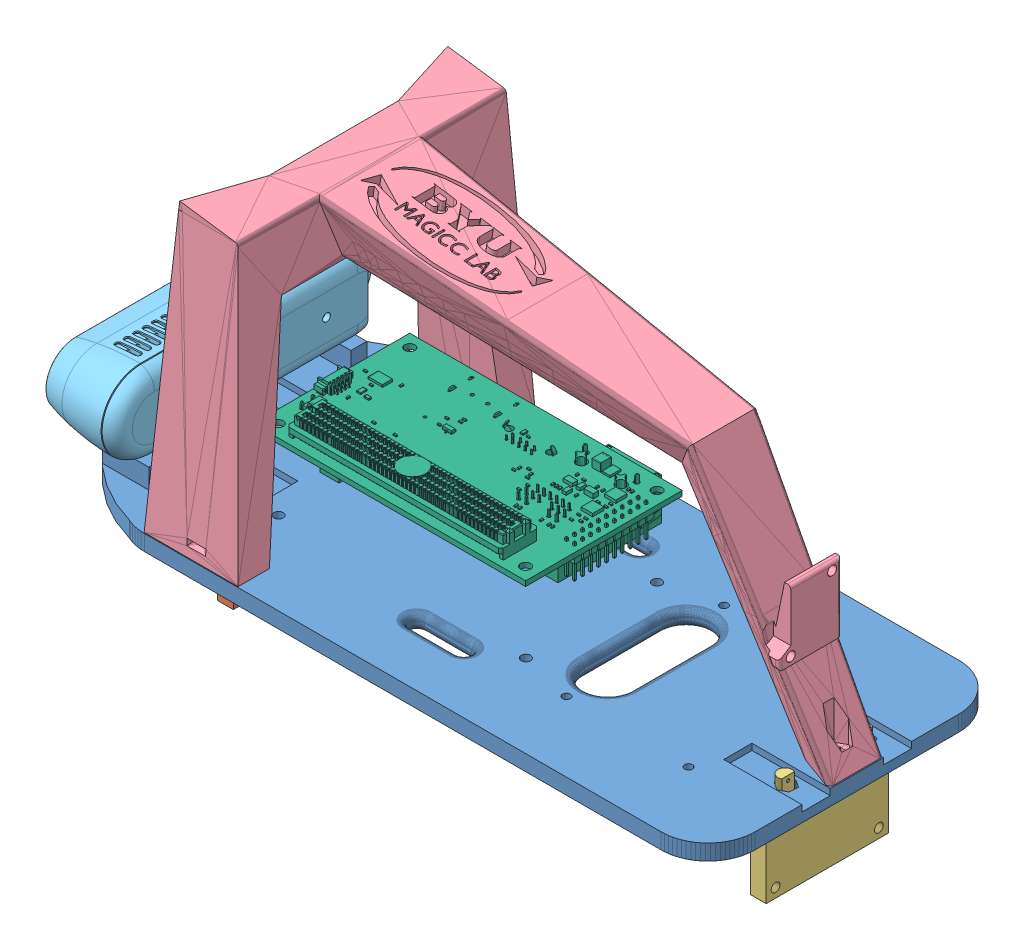
SolidWorks assembly donkeycar_cage, configuration Default. Lengths in mm.
Overall size (221.09 128.62 95.26).
6 component instances, 6 part files, 14 mates.
Components (placement in the parent):
- hackathon_baseplate-1: hackathon_baseplate [Default] at (106.7804 100.2943 141.8943) size (221.09 11.35 95)
- hackathon_front_bracket-1: hackathon_front_bracket [Default] at (107.0241 100.2943 141.9476) size (5 37 36.62)
- hackathon_back_bracket-1: hackathon_back_bracket [Default] at (106.4263 100.2943 141.9966) size (5 32 39)
- Magnet_Roll_Cage_v3-1: Magnet_Roll_Cage_v3 [Default] at (106.7804 100.2754 141.8943) size (180 92.62 95)
- Intel_RealSense_Depth_Camera_D435-1: Intel_RealSense_Depth_Camera_D435 [Default] at (-35.1196 124.1443 141.8943) x (0 0 1) z (-1 0 0) size (90.48 26.3 25.07)
- orbityboard-1: orbityboard [Default] at (101.1304 129.0937 167.0148) x (-1 0 0) z (0 -1 0) size (87.04 52.66 23.82)
Mates (geometry in assembly coordinates):
- Parallel1: parallel anti-aligned: plane of hackathon_baseplate-1 through (11.7804 103.2943 133.3943) normal (-1 0 0); plane of hackathon_front_bracket-1 through (1.0241 100.2943 141.9476) normal (1 0 0)
- Coincident2: coincident anti-aligned: plane of hackathon_front_bracket-1 through (107.0241 100.2943 141.9476) normal (0 1 0); plane of hackathon_baseplate-1 through (106.7804 100.2943 141.8943) normal (0 -1 0)
- Parallel2: parallel anti-aligned: plane of hackathon_baseplate-1 through (181.7804 100.2943 141.8943) normal (1 0 0); plane of hackathon_back_bracket-1 through (167.4263 100.2943 141.9966) normal (-1 0 0)
- Coincident4: coincident anti-aligned: plane of hackathon_baseplate-1 through (106.7804 100.2943 141.8943) normal (0 -1 0); plane of hackathon_back_bracket-1 through (167.5826 100.2943 156.7464) normal (0 1 0)
- Coincident5: coincident anti-aligned: plane of hackathon_baseplate-1 through (106.7804 105.2943 141.8943) normal (0 1 0); plane of Magnet_Roll_Cage_v3-1 through (106.7804 105.2943 141.8943) normal (0 -1 0)
- Coincident6: coincident: line of hackathon_baseplate-1 through (176.3063 100.2943 143.221) axis (-0.997121 0 -0.075827); plane of Magnet_Roll_Cage_v3-1 through (107.0798 100.2754 137.9566) normal (0.075827 0 -0.997121)
- Coincident7: coincident aligned: plane of hackathon_baseplate-1 through (174.6944 105.2943 143.0985) normal (0.901448 0 -0.432887); plane of Magnet_Roll_Cage_v3-1 through (161.498 100.2754 115.6182) normal (0.901448 0 -0.432887)
- Distance3: distance = 6.35 mm anti-aligned: plane of hackathon_baseplate-1 through (106.7804 105.2943 141.8943) normal (0 1 0); plane of Intel_RealSense_Depth_Camera_D435-1 through (-35.1196 111.6443 141.8943) normal (0 -1 0)
- Concentric1: concentric anti-aligned: cylinder of hackathon_baseplate-1 through (-20.2196 95.2943 141.8943) axis (0 1 0) radius 3.175; cylinder of Intel_RealSense_Depth_Camera_D435-1 through (-20.2196 111.6443 141.8943) axis (0 -1 0) radius 3.175
- Parallel4: parallel aligned: plane of hackathon_baseplate-1 through (11.7804 103.2943 133.3943) normal (-1 0 0); plane of Intel_RealSense_Depth_Camera_D435-1 through (-35.0196 124.1443 141.8943) normal (-1 0 0)
- Parallel5: parallel aligned: plane of hackathon_baseplate-1 through (106.7804 105.2943 141.8943) normal (0 1 0); plane of orbityboard-1 through (101.1304 130.6943 167.0148) normal (0 1 0)
- Parallel6: parallel aligned: plane of hackathon_baseplate-1 through (106.7804 100.2943 94.3943) normal (0 0 -1); plane of orbityboard-1 through (14.1304 130.6943 117.0148) normal (0 0 -1)
- Distance1: distance = 25.4 mm aligned: plane of orbityboard-1 through (101.1304 130.6943 167.0148) normal (0 1 0); plane of hackathon_baseplate-1 through (106.7804 105.2943 141.8943) normal (0 1 0)
- Concentric3: concentric aligned: cylinder of hackathon_baseplate-1 through (18.1304 100.2943 121.0148) axis (0 1 0) radius 1.5; cylinder of orbityboard-1 through (18.1304 130.6943 121.0148) axis (0 1 0) radius 1.6
